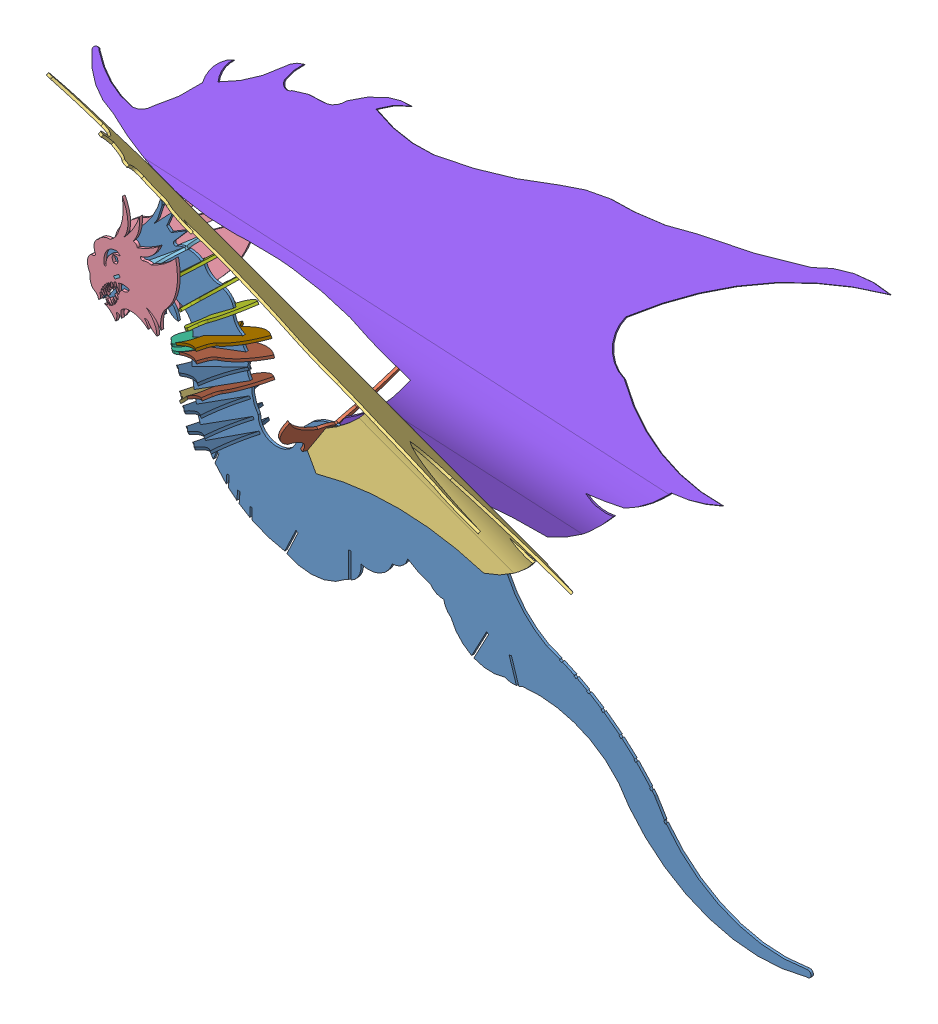
SolidWorks assembly _Assy, Dragon 03-d, configuration Default. Lengths in mm.
Overall size (473.6 292.37 279.35).
20 component instances, 12 part files, 53 mates.
Components (placement in the parent):
- Dragon 03-d, Spine-1: Dragon 03-d, Spine [Default] at (-209.7205 -139.397 -7.2234) size (449.42 225.82 1.52)
- Dragon 03-d, Wing Suppt Plt-1: Dragon 03-d, Wing Suppt Plt [Default] at (-182.8834 -156.6939 -7.375) x (0.105081 -0.069499 0.992032) z (-0.832131 0.54008 0.125981) size (79.31 53.53 11.91)
- Dragon 03-d, Wing-2: Dragon 03-d, Wing [Default] at (-259.9804 -185.0647 -7.0927) x (0.993495 0.008896 0.113524) z (-0.113871 0.072652 0.990836) size (396.42 152.24 107.33)
- Dragon 03-d, Face, Left-1: Dragon 03-d, Face, Left [Default] at (-291.1255 -30.6386 -32.064) x (-0.752911 -0.615847 -0.232073) z (-0.179635 -0.146933 0.972698) size (103.7 65.41 1.52)
- Dragon 03-d, Face, Tie-In Plt-1: Dragon 03-d, Face, Tie-In Plt [Default] at (-295.713 -34.391 -7.2234) x (0.774043 0.633133 0) z (-0.633133 0.774043 0) size (70.66 36.07 1.52)
- Dragon 03-d, Armor, Throat Plts-1: Dragon 03-d, Armor, Throat Plts [Default] at (-262.9161 -18.5187 -7.2234) x (0.898522 0.438928 0) z (-0.438928 0.898522 0) size (23.12 17.55 1.52)
- Dragon 03-d, Armor, Throat Plts-2: Dragon 03-d, Armor, Throat Plts [Default] at (-267.3355 -11.2792 -7.2234) x (0.935196 0.35413 0) z (-0.35413 0.935196 0) size (23.12 17.55 1.52)
- Dragon 03-d, Armor, Neck Plt-01-1: Dragon 03-d, Armor, Neck Plt-01 [Default] at (-287.4297 -56.4683 -7.2234) x (0.729697 0.683771 0) z (-0.683771 0.729697 0) size (46.56 29.78 1.52)
- Dragon 03-d, Armor, Neck Plt-01-2: Dragon 03-d, Armor, Neck Plt-01 [Default] at (-271.0491 -64.0565 -7.2234) x (0.718584 0.695441 0) z (-0.695441 0.718584 0) size (46.56 29.78 1.52)
- Dragon 03-d, Armor, Neck Plt-01-3: Dragon 03-d, Armor, Neck Plt-01 [Default] at (-282.6249 -54.4345 -7.2234) x (0.802429 0.596748 0) z (-0.596748 0.802429 0) size (46.56 29.78 1.52)
- MirrorDragon 03-d, Wing-3: MirrorDragon 03-d, Wing [Default] at (-259.9804 -185.0647 -5.83) x (0.993495 0.008896 -0.113524) z (0.113871 -0.072652 0.990836) size (396.42 152.24 107.33)
- Dragon 03-d, Face, Left-2: Dragon 03-d, Face, Left [Default] at (-291.3993 -30.8625 17.6589) x (-0.752911 -0.615847 0.232073) z (0.179635 0.146933 0.972698) size (103.7 65.41 1.52)
- Dragon 03-d, Armor, Neck Plt-03-1: Dragon 03-d, Armor, Neck Plt-03 [Default] at (-295.7589 -33.811 -7.2234) x (0.898217 0.439553 0) z (-0.439553 0.898217 0) size (56.92 29.78 1.52)
- Dragon 03-d, Armor, Throat Plt-04-5: Dragon 03-d, Armor, Throat Plt-04 [Default] at (-270.7023 -37.9625 -7.2234) x (0 0 1) z (-0.436699 0.899608 0) size (36.65 50.64 1.52)
- Dragon 03-d, Armor, Neck Plt-05-1: Dragon 03-d, Armor, Neck Plt-05 [Default] at (-282.5068 -75.7062 -5.6994) x (0.84342 0.537254 0) z (0.537254 -0.84342 0) size (54.35 29.78 1.52)
- Dragon 03-d, Armor, Throat Plt-05-6: Dragon 03-d, Armor, Throat Plt-05 [Default] at (-262.2604 -62.8094 -5.6994) x (0 0 -1) z (0.537254 -0.84342 0) size (27.57 27.74 1.52)
- Dragon 03-d, Armor, Neck Plt-05-2: Dragon 03-d, Armor, Neck Plt-05 [Default] at (-302.8791 -23.1089 -5.6994) x (0.935196 0.35413 0) z (0.35413 -0.935196 0) size (54.35 29.78 1.52)
- Dragon 03-d, Armor, Throat Plt-04-6: Dragon 03-d, Armor, Throat Plt-04 [Default] at (-260.3284 -69.7441 -5.6994) x (0 0 -1) z (0.537254 -0.84342 0) size (36.65 50.64 1.52)
- Dragon 03-d, Armor, Throat Plt-04-7: Dragon 03-d, Armor, Throat Plt-04 [Default] at (-258.091 -79.8069 -5.6994) x (0 0 -1) z (0.537254 -0.84342 0) size (36.65 50.64 1.52)
- Dragon 03-d, Armor, Throat Plt-04-8: Dragon 03-d, Armor, Throat Plt-04 [Default] at (-253.1693 -87.5168 -5.6994) x (0 0 -1) z (0.546496 -0.837462 0) size (36.65 50.64 1.52)
Mates (geometry in assembly coordinates):
- Coincident11: coincident anti-aligned: plane of Dragon 03-d, Wing Suppt Plt-1 through (-57.35 35.3035 0.0362) normal (0.113871 -0.072652 -0.990836); plane of Dragon 03-d, Wing-2 through (20.1723 -222.7259 27.865) normal (-0.113871 0.072652 0.990836)
- Coincident12: coincident anti-aligned: plane of Dragon 03-d, Wing Suppt Plt-1 through (-60.6342 29.8668 -1.4807) normal (0.544532 0.838739 0.00108); plane of Dragon 03-d, Wing-2 through (-61.9007 30.6893 -1.6866) normal (-0.544532 -0.838739 -0.00108)
- Coincident13: coincident aligned: plane of Dragon 03-d, Wing Suppt Plt-1 through (-75.0697 12.312 5.9067) normal (-0.830974 0.539665 -0.135069); plane of Dragon 03-d, Wing-2 through (-219.3503 -211.4514 -0.4886) normal (-0.830974 0.539665 -0.135069)
- Coincident18: coincident: moEndPointRef_w of Dragon 03-d, Spine-1; moEndPointRef_w of Dragon 03-d, Wing Suppt Plt-1
- Coincident19: coincident: point of Dragon 03-d, Spine-1; plane of Dragon 03-d, Wing Suppt Plt-1 through (-71.0492 9.7018 5.8788) normal (0.832131 -0.54008 -0.125981)
- Coincident20: coincident: point of Dragon 03-d, Spine-1; plane of Dragon 03-d, Wing Suppt Plt-1 through (-73.8033 11.4896 6.1125) normal (0.830974 -0.539665 0.135069)
- Lock2: lock: unknown of Dragon 03-d, Spine-1; unknown of Dragon 03-d, Wing Suppt Plt-1
- Coincident23: coincident anti-aligned: plane of Dragon 03-d, Spine-1 through (-180.543 61.7818 -5.6994) normal (0.633133 -0.774043 0); plane of Dragon 03-d, Face, Tie-In Plt-1 through (-140.4525 94.5741 -18.1687) normal (-0.633133 0.774043 0)
- Coincident24: coincident anti-aligned: plane of Dragon 03-d, Spine-1 through (-166.7101 23.4417 -5.6994) normal (0 0 1); plane of Dragon 03-d, Face, Tie-In Plt-1 through (-204.098 42.5149 -5.6994) normal (0 0 -1)
- Coincident25: coincident anti-aligned: plane of Dragon 03-d, Spine-1 through (-179.5781 60.6022 -5.6994) normal (0.774043 0.633133 0); plane of Dragon 03-d, Face, Tie-In Plt-1 through (-180.543 61.7818 -5.6994) normal (-0.774043 -0.633133 0)
- Coincident26: coincident aligned: plane of Dragon 03-d, Face, Left-1 through (-291.3993 -30.8625 -30.5816) normal (-0.179635 -0.146933 0.972698); plane of Dragon 03-d, Face, Tie-In Plt-1 through (-186.083 57.2503 2.1779) normal (-0.179635 -0.146933 0.972698)
- Coincident27: coincident anti-aligned: plane of Dragon 03-d, Face, Left-1 through (-292.3642 -29.6829 -30.5816) normal (0.633133 -0.774043 0); plane of Dragon 03-d, Face, Tie-In Plt-1 through (-140.4525 94.5741 -18.1687) normal (-0.633133 0.774043 0)
- Coincident28: coincident anti-aligned: plane of Dragon 03-d, Face, Left-1 through (-185.1181 56.0707 2.1779) normal (0.752911 0.615847 0.232073); plane of Dragon 03-d, Face, Tie-In Plt-1 through (-185.7468 57.5254 0.3573) normal (-0.752911 -0.615847 -0.232073)
- Coincident29: coincident anti-aligned: plane of Dragon 03-d, Spine-1 through (-144.256 41.1429 -5.6994) normal (0.438928 -0.898522 0); plane of Dragon 03-d, Armor, Throat Plts-1 through (-133.6807 46.3089 -12.0075) normal (-0.438928 0.898522 0)
- Coincident30: coincident anti-aligned: plane of Dragon 03-d, Spine-1 through (-166.7101 23.4417 -7.2234) normal (0 0 -1); plane of Dragon 03-d, Armor, Throat Plts-1 through (-138.9473 43.7362 -7.2234) normal (0 0 1)
- Coincident31: coincident anti-aligned: plane of Dragon 03-d, Spine-1 through (-138.9473 43.7362 -5.6994) normal (-0.898522 -0.438928 0); plane of Dragon 03-d, Armor, Throat Plts-1 through (-138.9473 43.7362 -6.4614) normal (0.898522 0.438928 0)
- Coincident33: coincident anti-aligned: plane of Dragon 03-d, Spine-1 through (-166.7101 23.4417 -7.2234) normal (0 0 -1); plane of Dragon 03-d, Armor, Throat Plts-2 through (-138.1502 39.2689 -7.2234) normal (0 0 1)
- Coincident38: coincident anti-aligned: plane of Dragon 03-d, Spine-1 through (-138.7781 84.9158 -5.6994) normal (0.683771 -0.729697 0); plane of Dragon 03-d, Armor, Neck Plt-01-1 through (-160.9951 64.0972 -14.5866) normal (-0.683771 0.729697 0)
- Coincident39: coincident anti-aligned: plane of Dragon 03-d, Spine-1 through (-166.7101 23.4417 -7.2234) normal (0 0 -1); plane of Dragon 03-d, Armor, Neck Plt-01-1 through (-144.073 79.9542 -7.2234) normal (0 0 1)
- Coincident40: coincident anti-aligned: plane of Dragon 03-d, Spine-1 through (-143.0309 78.8422 -5.6994) normal (0.729697 0.683771 0); plane of Dragon 03-d, Armor, Neck Plt-01-1 through (-144.073 79.9542 -7.2234) normal (-0.729697 -0.683771 0)
- Coincident41: coincident anti-aligned: plane of Dragon 03-d, Spine-1 through (-128.8495 73.5633 -5.6994) normal (0.718584 0.695441 0); plane of Dragon 03-d, Armor, Neck Plt-01-2 through (-129.9093 74.6584 -7.2234) normal (-0.718584 -0.695441 0)
- Coincident42: coincident anti-aligned: plane of Dragon 03-d, Spine-1 through (-166.7101 23.4417 -5.6994) normal (0 0 1); plane of Dragon 03-d, Armor, Neck Plt-01-2 through (-129.9093 74.6584 -5.6994) normal (0 0 -1)
- Coincident43: coincident anti-aligned: plane of Dragon 03-d, Spine-1 through (-126.5139 77.9445 -5.6994) normal (0.695441 -0.718584 0); plane of Dragon 03-d, Armor, Neck Plt-01-2 through (-146.5737 58.5308 -14.5866) normal (-0.695441 0.718584 0)
- Coincident44: coincident anti-aligned: plane of Dragon 03-d, Spine-1 through (-119.0309 67.2266 -5.6994) normal (-0.596748 0.802429 0); plane of Dragon 03-d, Armor, Neck Plt-01-3 through (-142.4421 49.8162 -14.5866) normal (0.596748 -0.802429 0)
- Coincident45: coincident anti-aligned: plane of Dragon 03-d, Spine-1 through (-166.7101 23.4417 -5.6994) normal (0 0 1); plane of Dragon 03-d, Armor, Neck Plt-01-3 through (-124.7427 64.878 -5.6994) normal (0 0 -1)
- Coincident46: coincident anti-aligned: plane of Dragon 03-d, Spine-1 through (-123.8333 63.6551 -5.6994) normal (0.802429 0.596748 0); plane of Dragon 03-d, Armor, Neck Plt-01-3 through (-124.7427 64.878 -7.2234) normal (-0.802429 -0.596748 0)
- Coincident47: coincident anti-aligned: plane of Dragon 03-d, Spine-1 through (-166.7101 23.4417 -7.2234) normal (0 0 -1); plane of Dragon 03-d, Armor, Neck Plt-03-1 through (-118.6818 54.5404 -7.2234) normal (0 0 1)
- Coincident48: coincident anti-aligned: moEndPointRef_w of Dragon 03-d, Armor, Neck Plt-03-1; line of Dragon 03-d, Spine-1 through (-118.6818 54.5404 -5.6994) axis (0 0 -1)
- Coincident66: coincident anti-aligned: plane of Dragon 03-d, Spine-1 through (-114.5942 29.4462 -5.6994) normal (-0.537254 0.84342 0); plane of Dragon 03-d, Armor, Neck Plt-05-1 through (-128.2494 20.7479 -11.1015) normal (0.537254 -0.84342 0)
- Coincident67: coincident anti-aligned: plane of Dragon 03-d, Spine-1 through (-166.7101 23.4417 -5.6994) normal (0 0 1); plane of Dragon 03-d, Armor, Neck Plt-05-1 through (-114.7847 29.3249 -5.6994) normal (0 0 -1)
- Coincident69: coincident: moEndPointRef_w of Dragon 03-d, Spine-1; moEndPointRef_w of Dragon 03-d, Armor, Neck Plt-05-1
- Coincident71: coincident anti-aligned: plane of Dragon 03-d, Spine-1 through (-143.1111 11.2811 -5.6994) normal (-0.537254 0.84342 0); plane of Dragon 03-d, Armor, Throat Plt-05-6 through (-128.2178 20.7681 -1.8212) normal (0.537254 -0.84342 0)
- Coincident72: coincident anti-aligned: plane of Dragon 03-d, Spine-1 through (-138.4344 16.0671 -5.6994) normal (-0.84342 -0.537254 0); plane of Dragon 03-d, Armor, Throat Plt-05-6 through (-137.6157 14.7817 -6.4614) normal (0.84342 0.537254 0)
- Coincident73: coincident anti-aligned: plane of Dragon 03-d, Spine-1 through (-117.8143 46.9694 -5.6994) normal (0.935196 0.35413 0); plane of Dragon 03-d, Armor, Neck Plt-05-2 through (-117.2746 45.5442 -5.6994) normal (-0.935196 -0.35413 0)
- Coincident74: coincident anti-aligned: plane of Dragon 03-d, Spine-1 through (-166.7101 23.4417 -7.2234) normal (0 0 -1); plane of Dragon 03-d, Armor, Neck Plt-05-2 through (-133.2055 39.5117 -7.2234) normal (0 0 1)
- Coincident75: coincident anti-aligned: plane of Dragon 03-d, Spine-1 through (-117.8143 46.9694 -5.6994) normal (0.35413 -0.935196 0); plane of Dragon 03-d, Armor, Neck Plt-05-2 through (-132.7442 41.316 -11.1015) normal (-0.35413 0.935196 0)
- Coincident76: coincident anti-aligned: plane of Dragon 03-d, Spine-1 through (-144.7665 35.1339 -5.6994) normal (-0.35413 0.935196 0); plane of Dragon 03-d, Armor, Throat Plts-2 through (-132.129 39.9193 -12.0075) normal (0.35413 -0.935196 0)
- Coincident77: coincident anti-aligned: plane of Dragon 03-d, Spine-1 through (-166.7101 23.4417 -5.6994) normal (0 0 1); plane of Dragon 03-d, Armor, Throat Plts-2 through (-138.1502 39.2689 -5.6994) normal (0 0 -1)
- Coincident78: coincident anti-aligned: plane of Dragon 03-d, Spine-1 through (-138.1502 39.2689 -5.6994) normal (-0.935196 -0.35413 0); plane of Dragon 03-d, Armor, Throat Plts-2 through (-138.1502 39.2689 -6.4614) normal (0.935196 0.35413 0)
- Coincident79: coincident anti-aligned: plane of Dragon 03-d, Spine-1 through (-112.7309 57.4525 -5.6994) normal (0.439553 -0.898217 0); plane of Dragon 03-d, Armor, Neck Plt-03-1 through (-134.0322 47.0285 -0.9152) normal (-0.439553 0.898217 0)
- Coincident82: coincident anti-aligned: plane of Dragon 03-d, Spine-1 through (-166.7101 23.4417 -7.2234) normal (0 0 -1); plane of Dragon 03-d, Armor, Throat Plt-05-6 through (-137.6157 14.7817 -7.2234) normal (0 0 1)
- Coincident83: coincident anti-aligned: plane of Dragon 03-d, Spine-1 through (-141.8582 5.7207 -5.6994) normal (0.537254 -0.84342 0); plane of Dragon 03-d, Armor, Throat Plt-04-6 through (-99.9094 32.4419 19.6429) normal (-0.537254 0.84342 0)
- Coincident84: coincident anti-aligned: plane of Dragon 03-d, Spine-1 through (-166.7101 23.4417 -7.2234) normal (0 0 -1); plane of Dragon 03-d, Armor, Throat Plt-04-6 through (-135.6837 7.8469 -7.2234) normal (0 0 1)
- Coincident85: coincident anti-aligned: plane of Dragon 03-d, Spine-1 through (-136.5025 9.1323 -5.6994) normal (-0.84342 -0.537254 0); plane of Dragon 03-d, Armor, Throat Plt-04-6 through (-135.6837 7.8469 -6.4614) normal (0.84342 0.537254 0)
- Coincident91: coincident anti-aligned: plane of Dragon 03-d, Spine-1 through (-144.7768 24.8598 -5.6994) normal (0.436699 -0.899608 0); plane of Dragon 03-d, Armor, Throat Plt-04-5 through (-100.2619 46.4688 -32.5656) normal (-0.436699 0.899608 0)
- Coincident92: coincident anti-aligned: plane of Dragon 03-d, Spine-1 through (-166.7101 23.4417 -5.6994) normal (0 0 1); plane of Dragon 03-d, Armor, Throat Plt-04-5 through (-139.2928 27.5219 -5.6994) normal (0 0 -1)
- Coincident93: coincident anti-aligned: plane of Dragon 03-d, Spine-1 through (-139.2928 27.5219 -5.6994) normal (-0.899608 -0.436699 0); plane of Dragon 03-d, Armor, Throat Plt-04-5 through (-139.2928 27.5219 -6.4614) normal (0.899608 0.436699 0)
- Coincident94: coincident: plane of Dragon 03-d, Spine-1 through (-139.4065 -4.2056 -5.6994) normal (0.537254 -0.84342 0); plane of Dragon 03-d, Armor, Throat Plt-04-7 through (-97.6719 22.3791 19.6429) normal (-0.537254 0.84342 0)
- Coincident95: coincident: plane of Dragon 03-d, Spine-1 through (-166.7101 23.4417 -7.2234) normal (0 0 -1); plane of Dragon 03-d, Armor, Throat Plt-04-7 through (-133.4463 -2.2159 -7.2234) normal (0 0 1)
- Coincident96: coincident anti-aligned: plane of Dragon 03-d, Spine-1 through (-133.3723 -2.332 -5.6994) normal (-0.84342 -0.537254 0); plane of Dragon 03-d, Armor, Throat Plt-04-7 through (-133.4463 -2.2159 -6.4614) normal (0.84342 0.537254 0)
- Coincident97: coincident: plane of Dragon 03-d, Spine-1 through (-136.1945 -11.1834 -5.6994) normal (0.546496 -0.837462 0); plane of Dragon 03-d, Armor, Throat Plt-04-8 through (-93.8836 16.4271 19.6429) normal (-0.546496 0.837462 0)
- Coincident98: coincident: plane of Dragon 03-d, Spine-1 through (-166.7101 23.4417 -5.6994) normal (0 0 1); plane of Dragon 03-d, Armor, Throat Plt-04-8 through (-129.3854 -8.5598 -5.6994) normal (0 0 -1)
- Coincident99: coincident anti-aligned: plane of Dragon 03-d, Spine-1 through (-129.3001 -8.6905 -5.6994) normal (-0.837462 -0.546496 0); plane of Dragon 03-d, Armor, Throat Plt-04-8 through (-129.3854 -8.5598 -6.4614) normal (0.837462 0.546496 0)
